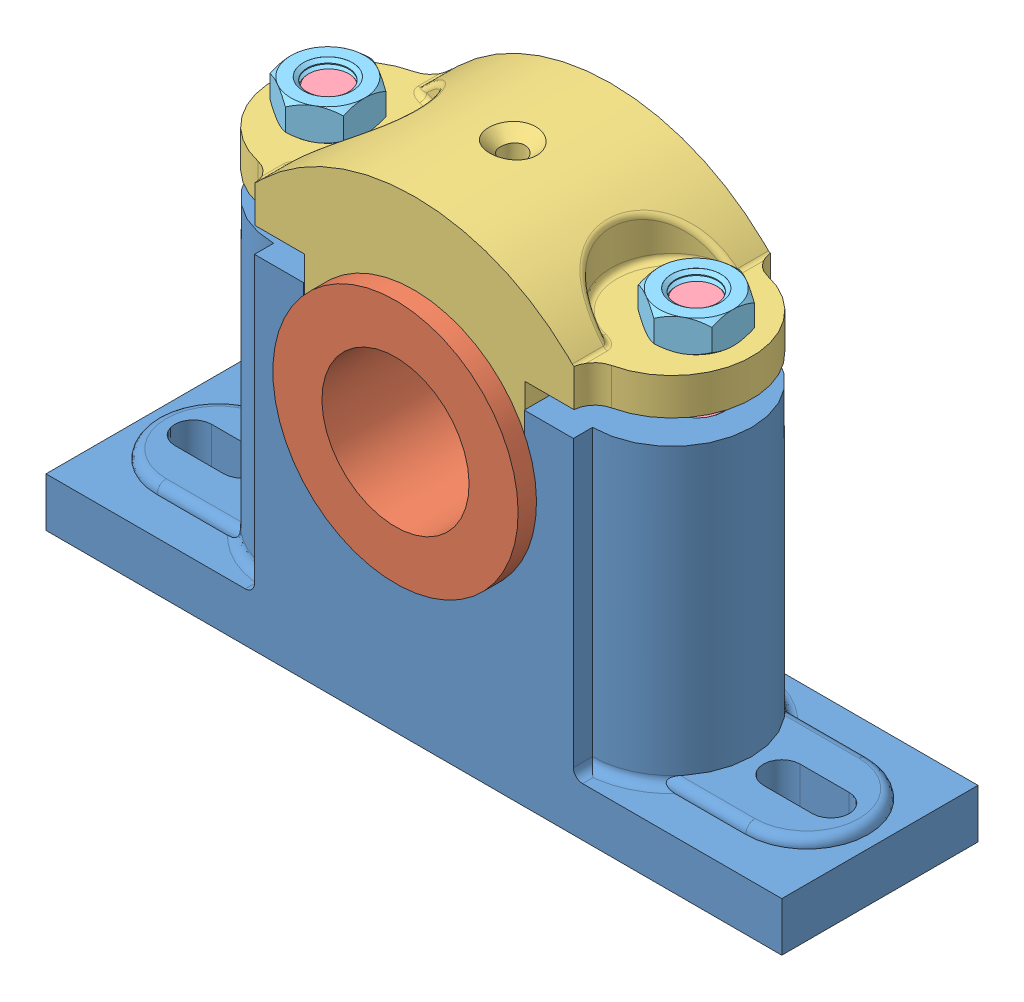
SolidWorks assembly Pedestal Bearing Assembly, configuration Default. Lengths in mm.
Overall size (190.5 122.4 60.32).
7 component instances, 5 part files, 16 mates.
Components (placement in the parent):
- Pedestal Bearing-Base-1: Pedestal Bearing-Base [Default] at origin size (190.5 88.9 50.8)
- Pedestal Bearing Bushing-1: Pedestal Bearing Bushing [Default] at (0 57.15 0) x (0 0 -1) z (-0.952302 0.305158 0) size (60.32 63.5 63.5)
- Pedestal Bearing-Cap-1: Pedestal Bearing-Cap [Default] at (28.575 57.15 25.2088) size (123.82 52.55 50.8)
- heavy hex bolt_ai-1: heavy hex bolt_ai [HHBOLT 0.5000-13x4x1-S] at (47.625 -12.7 -0.1912) x (0 1 0) z (-0.5 0 0.866025) size (110.85 25.66 22.23)
- heavy hex bolt_ai-3: heavy hex bolt_ai [HHBOLT 0.5000-13x4x1-S] at (-47.625 -12.7 -0.1912) x (0 1 0) z (-0.5 0 0.866025) size (110.85 25.66 22.23)
- hex jam nut_ai-1: hex jam nut_ai [HJNUT 0.5000-13-D-S] at (47.5874 92.075 -0.1233) x (1 0 0) z (0 -1 0) size (19.05 22 8.2)
- hex jam nut_ai-2: hex jam nut_ai [HJNUT 0.5000-13-D-S] at (-47.5172 92.075 0.1653) x (1 0 0) z (0 -1 0) size (19.05 22 8.2)
Mates (geometry in assembly coordinates):
- Concentric1: concentric anti-aligned: cylinder of Pedestal Bearing-Base-1 through (0 57.15 106.2223) axis (0 0 -1) radius 23.8125; cylinder of Pedestal Bearing Bushing-1 through (0 57.15 30.1625) axis (0 0 1) radius 23.8125
- Coincident1: coincident anti-aligned: plane of Pedestal Bearing-Base-1 through (95.25 -12.7 25.4) normal (0 0 1); plane of Pedestal Bearing Bushing-1 through (-7.2666 34.4733 25.4) normal (0 0 -1)
- Coincident6: coincident anti-aligned: plane of Pedestal Bearing-Base-1 through (23.8125 57.15 106.2223) normal (0 1 0); plane of Pedestal Bearing-Cap-1 through (28.575 57.15 -25.5912) normal (0 -1 0)
- Coincident7: coincident anti-aligned: plane of Pedestal Bearing-Base-1 through (28.575 76.2 -25.4) normal (-1 0 0); plane of Pedestal Bearing-Cap-1 through (28.575 57.15 -25.5912) normal (1 0 0)
- Concentric2: concentric anti-aligned: cylinder of Pedestal Bearing-Base-1 through (47.625 76.2 -0.1912) axis (0 -1 0) radius 7.1437; cylinder of Pedestal Bearing-Cap-1 through (47.625 41.275 -0.1912) axis (0 1 0) radius 6.1882
- Concentric5: concentric aligned: cylinder of Pedestal Bearing-Base-1 through (47.625 76.2 -0.1912) axis (0 -1 0) radius 7.1437; cylinder of heavy hex bolt_ai-1 through (47.625 -12.7 -0.1912) axis (0 -1 0) radius 6.35
- Coincident9: coincident aligned: plane of Pedestal Bearing-Base-1 through (0 -12.7 0) normal (0 -1 0); plane of heavy hex bolt_ai-1 through (36.5125 -12.7 -6.607) normal (0 -1 0)
- Parallel5: parallel anti-aligned: plane of Pedestal Bearing-Base-1 through (47.625 -3.175 -13.9393) normal (0.5 0 0.866025); plane of heavy hex bolt_ai-1 through (47.625 -3.4544 -13.0228) normal (-0.5 0 -0.866025)
- Concentric6: concentric aligned: cylinder of Pedestal Bearing-Base-1 through (-47.625 76.2 -0.1912) axis (0 -1 0) radius 7.1437; cylinder of heavy hex bolt_ai-3 through (-47.625 -12.7 -0.1912) axis (0 -1 0) radius 6.35
- Parallel6: parallel anti-aligned: plane of Pedestal Bearing-Base-1 through (-59.5312 -3.175 -7.0652) normal (0.5 0 0.866025); plane of heavy hex bolt_ai-3 through (-47.625 -3.4544 -13.0228) normal (-0.5 0 -0.866025)
- Coincident13: coincident aligned: plane of Pedestal Bearing-Base-1 through (0 -12.7 0) normal (0 -1 0); plane of heavy hex bolt_ai-3 through (-58.7375 -12.7 -6.607) normal (0 -1 0)
- Coincident14: coincident anti-aligned: plane of Pedestal Bearing-Cap-1 through (-41.275 92.075 -25.5912) normal (0 1 0); plane of hex jam nut_ai-2 through (-66.5672 92.075 0.1653) normal (0 -1 0)
- Parallel13: parallel aligned: plane of heavy hex bolt_ai-3 through (-47.625 98.1456 -0.1912) normal (0 1 0); plane of hex jam nut_ai-2 through (-66.5672 100.2792 0.1653) normal (0 1 0)
- Lock1: lock: unknown of heavy hex bolt_ai-3; unknown of hex jam nut_ai-2
- Coincident26: coincident: plane of Pedestal Bearing-Cap-1 through (61.9125 92.075 -25.5912) normal (0 1 0); plane of hex jam nut_ai-1 through (28.5374 92.075 -0.1233) normal (0 -1 0)
- Lock3: lock: unknown of heavy hex bolt_ai-1; unknown of hex jam nut_ai-1
